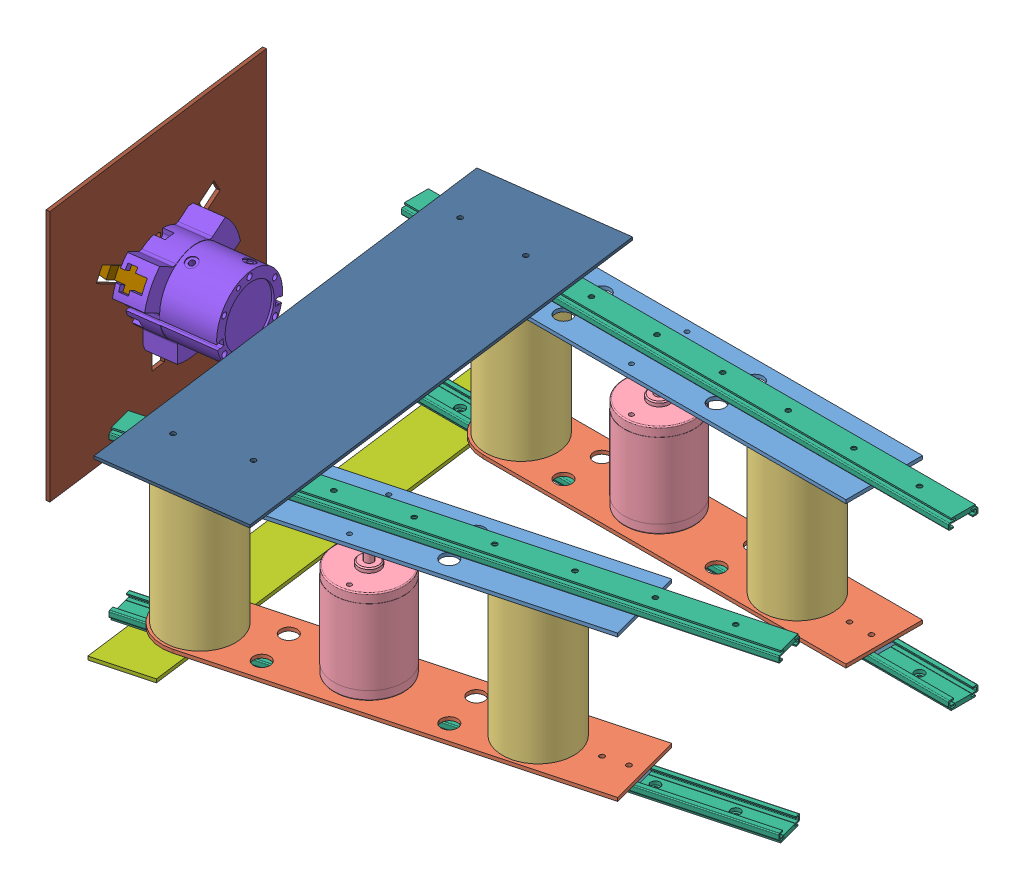
SolidWorks assembly Intake, configuration Default. Lengths in mm.
Overall size (635.12 250.6 426.13).
29 component instances, 11 part files, 8 mates.
Components (placement in the parent):
- armLayout-1: armLayout [Default] at (148.7009 655.9622 595.7013) size (527.6 155.43 422.82)
  - pneumaticShaft-1: pneumaticShaft [Default] at (70.702 114.2642 -26.093) size (366.97 144.05 70)
    - topPlate-1: topPlate [Default] at (83.6152 147.0048 280.3565) size (366.97 3.17 70)
    - bottomPlate-1: bottomPlate [Default] at (83.6152 16.8298 280.3565) size (366.97 3.17 70)
    - shaft-1: shaft [Default] at (209.8734 20.0048 280.3565) x (0.999976 0 -0.006968) z (0.006968 0 0.999976) size (65 127 65)
    - shaft-2: shaft [Default] at (-42.643 20.0048 280.3565) size (65 127 65)
    - Mini CIM-1: Mini CIM [Default] at (83.6152 110.0064 280.3565) x (0 -1 0) z (1 0 0) size (125.82 64.01 64.01)
    - 6723K110_LOW-PROFILE SLEEVE BEARING CARRIAGE-1: 6723K110_LOW-PROFILE SLEEVE BEARING CARRIAGE [6723K11] at (267.5734 7.3798 280.3565) x (0 0 1) z (-1 0 0) size (23.9 5.35 40)
    - 6723K110_LOW-PROFILE SLEEVE BEARING CARRIAGE-2: 6723K110_LOW-PROFILE SLEEVE BEARING CARRIAGE [6723K11] at (267.5734 159.6298 280.3565) x (0 0 -1) z (-1 0 0) size (23.9 5.35 40)
  - pneumaticShaft-2: pneumaticShaft [Default] at (0.1068 114.2642 269.526) x (0.965926 0 -0.258819) z (0.258819 0 0.965926) size (366.97 144.05 70)
    - topPlate-1: topPlate [Default] at (83.6152 147.0048 280.3565) size (366.97 3.17 70)
    - bottomPlate-1: bottomPlate [Default] at (83.6152 16.8298 280.3565) size (366.97 3.17 70)
    - shaft-1: shaft [Default] at (209.8734 20.0048 280.3565) x (0.999976 0 -0.006968) z (0.006968 0 0.999976) size (65 127 65)
    - shaft-2: shaft [Default] at (-42.643 20.0048 280.3565) size (65 127 65)
    - Mini CIM-1: Mini CIM [Default] at (83.6152 110.0064 280.3565) x (0 -1 0) z (1 0 0) size (125.82 64.01 64.01)
    - 6723K110_LOW-PROFILE SLEEVE BEARING CARRIAGE-1: 6723K110_LOW-PROFILE SLEEVE BEARING CARRIAGE [6723K11] at (267.5734 7.3798 280.3565) x (0 0 1) z (-1 0 0) size (23.9 5.35 40)
    - 6723K110_LOW-PROFILE SLEEVE BEARING CARRIAGE-2: 6723K110_LOW-PROFILE SLEEVE BEARING CARRIAGE [6723K11] at (267.5734 159.6298 280.3565) x (0 0 -1) z (-1 0 0) size (23.9 5.35 40)
  - 6723K210_LOW-PROFILE SLEEVE BEARING RAIL-1: 6723K210_LOW-PROFILE SLEEVE BEARING RAIL [6723K21] at (182.3199 121.644 254.3136) x (0 0 1) z (-1 0 0) size (27 8.7 500)
  - 6723K210_LOW-PROFILE SLEEVE BEARING RAIL-2: 6723K210_LOW-PROFILE SLEEVE BEARING RAIL [6723K21] at (214.9487 273.894 502.154) x (-0.258819 0 -0.965926) z (-0.965926 0 0.258819) size (27 8.7 500)
  - 6723K210_LOW-PROFILE SLEEVE BEARING RAIL-3: 6723K210_LOW-PROFILE SLEEVE BEARING RAIL [6723K21] at (214.9487 121.644 502.154) x (0.258819 0 0.965926) z (-0.965926 0 0.258819) size (27 8.7 500)
  - 6723K210_LOW-PROFILE SLEEVE BEARING RAIL-4: 6723K210_LOW-PROFILE SLEEVE BEARING RAIL [6723K21] at (182.3199 273.894 254.3136) x (0 0 -1) z (-1 0 0) size (27 8.7 500)
  - bottomSpacer-1: bottomSpacer [Default] at (-7.7879 118.469 405.4098) x (-0.130526 0 -0.991445) z (0.991445 0 -0.130526) size (419.78 3.17 50.8)
- Air_Gripper_Assembly-1: Air_Gripper_Assembly [Default] at (77.2757 910.6594 1000.6112) x (0.991445 0 -0.130526) z (0.130526 -0.000014 0.991445) size (100.53 94.6 107)
  - Air_Gripper_Body-1: Air_Gripper_Body [Default] at (2.7288 -0.6305 1.3862) size (74.5 90.6 101.7)
  - Air_Gripper_Grip-1: Air_Gripper_Grip [Default] at (-58.2712 16.3695 30.831) x (1 0 0) z (0 0.866025 -0.5) size (49.23 44 20)
  - Air_Gripper_Grip-2: Air_Gripper_Grip [Default] at (-58.2712 -34.6305 1.3862) size (49.23 44 20)
  - Air_Gripper_Grip-3: Air_Gripper_Grip [Default] at (-58.2712 16.3695 -28.0587) x (1 0 0) z (0 0.866025 0.5) size (49.23 44 20)
- railGripTop-1: railGripTop [Default] at (178.6871 929.8562 996.138) x (-0.130526 0 -0.991445) z (0.991445 0 -0.130526) size (406.4 2.54 127)
- intakeFrontPlate-1: intakeFrontPlate [Default] at (6.2995 910.0289 1011.3539) x (0.130526 0 0.991445) z (-0.991445 0 0.130526) size (230 230 3.17)
Mates (geometry in assembly coordinates):
- Concentric1: concentric anti-aligned: cylinder of armLayout-1/6723K210_LOW-PROFILE SLEEVE BEARING RAIL-4 through (121.0208 929.8562 850.0149) axis (0 1 0) radius 2.25; cylinder of railGripTop-1 through (121.0208 932.3962 850.0149) axis (0 -1 0) radius 2.25
- Coincident3: coincident anti-aligned: plane of armLayout-1/6723K210_LOW-PROFILE SLEEVE BEARING RAIL-4 through (81.0208 929.8562 861.0149) normal (0 1 0); plane of railGripTop-1 through (178.6871 929.8562 996.138) normal (0 -1 0)
- Concentric5: concentric anti-aligned: cylinder of armLayout-1/6723K210_LOW-PROFILE SLEEVE BEARING RAIL-2 through (160.8052 929.8562 1152.2073) axis (0 1 0) radius 2.25; cylinder of railGripTop-1 through (160.8052 932.3962 1152.2073) axis (0 -1 0) radius 2.25
- Coincident4: coincident anti-aligned: plane of Air_Gripper_Assembly-1/Air_Gripper_Body-1 through (6.2995 959.0289 1011.3542) normal (-0.991445 0 0.130526); plane of intakeFrontPlate-1 through (6.2995 910.0289 1011.3539) normal (0.991445 0 -0.130526)
- Coincident5: coincident: cylinder of Air_Gripper_Assembly-1/Air_Gripper_Body-1 through (6.2995 941.0289 1011.3539) axis (0.991445 0 -0.130526) radius 2.75; circle of intakeFrontPlate-1
- Coincident6: coincident: cylinder of Air_Gripper_Assembly-1/Air_Gripper_Body-1 through (9.8036 894.5286 1037.9704) axis (0.991445 0 -0.130526) radius 2.75; circle of intakeFrontPlate-1
- Parallel2: parallel aligned: plane of railGripTop-1 through (178.6871 932.3962 996.138) normal (0 1 0); plane of intakeFrontPlate-1 through (21.31 1025.0289 1125.3701) normal (0 1 0)
- Parallel3: parallel aligned: plane of railGripTop-1 through (205.21 932.3962 1197.5996) normal (0.130526 0 0.991445); plane of intakeFrontPlate-1 through (21.31 795.0289 1125.3701) normal (0.130526 0 0.991445)
